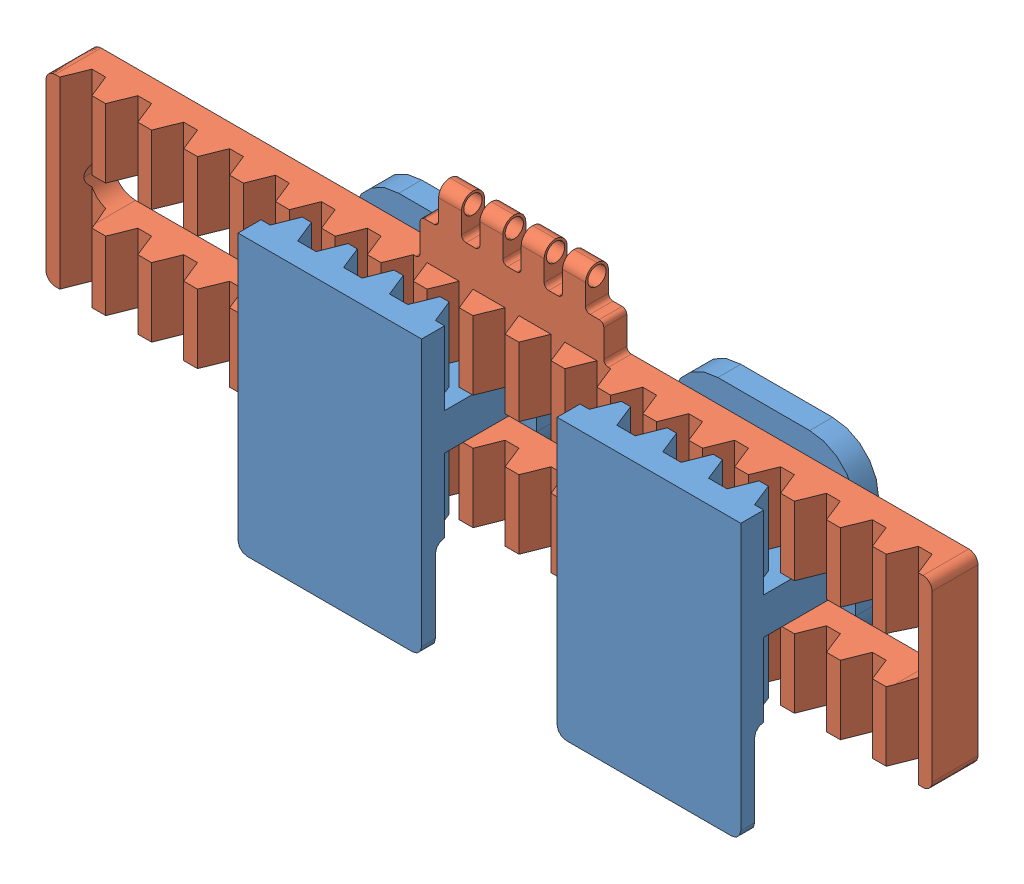
SolidWorks assembly locking_mechanism2, configuration Default. Lengths in mm.
Overall size (193 76 30).
3 component instances, 2 part files, 4 mates.
Components (placement in the parent):
- thigh_lock2-1: thigh_lock2 [Default] at (103.7037 111.3616 159.549) x (1 0 0) z (0 0 -1) size (40 60 30)
- thigh_lock2-2: thigh_lock2 [Default] at (34.1941 111.3616 159.549) x (1 0 0) z (0 0 -1) size (40 60 30)
- lock2_hinged-1: lock2_hinged [Default] at (71.874 71.3616 154.549) size (193 56 10)
Mates (geometry in assembly coordinates):
- Coincident1: coincident aligned: plane of thigh_lock2-2 through (34.1941 111.3616 159.549) normal (0 1 0); plane of lock2_hinged-1 through (71.874 111.3616 154.549) normal (0 1 0)
- Coincident2: coincident aligned: plane of thigh_lock2-1 through (103.7037 111.3616 159.549) normal (0 1 0); plane of lock2_hinged-1 through (71.874 111.3616 154.549) normal (0 1 0)
- Distance1: distance = 5 mm anti-aligned: plane of lock2_hinged-1 through (168.374 111.3616 149.549) normal (0 0 -1); plane of thigh_lock2-2 through (67.1941 71.3616 144.549) normal (0 0 1)
- Distance2: distance = 5 mm anti-aligned: plane of thigh_lock2-1 through (136.7037 71.3616 144.549) normal (0 0 1); plane of lock2_hinged-1 through (168.374 111.3616 149.549) normal (0 0 -1)
